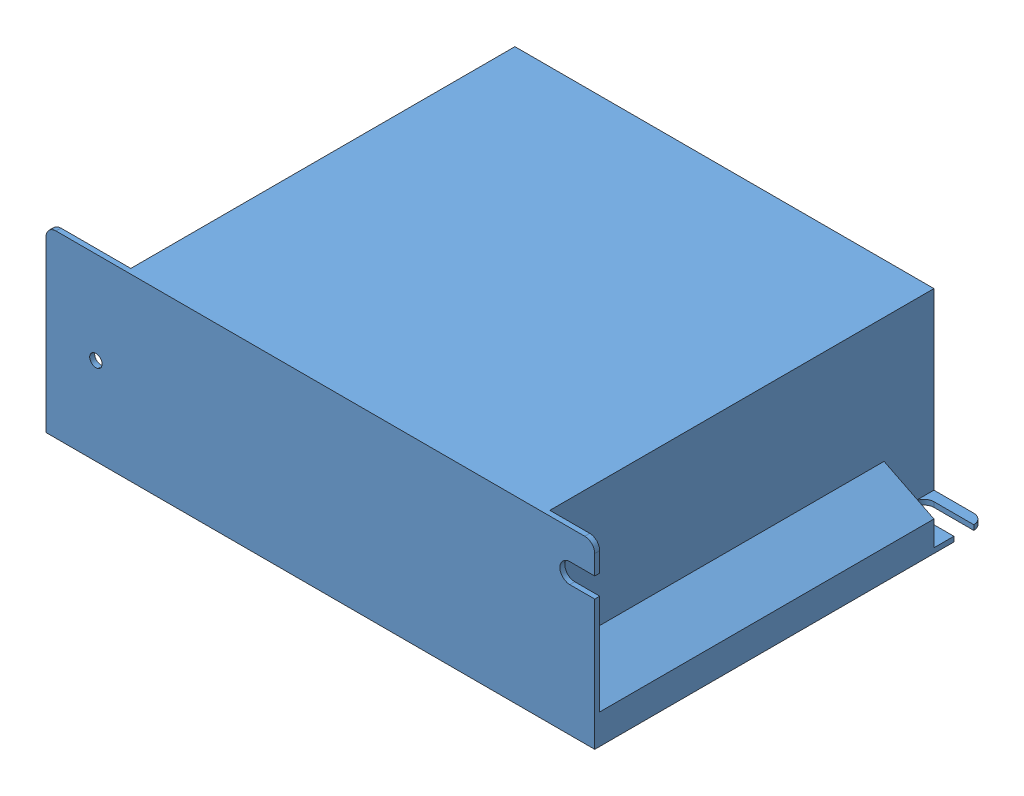
SolidWorks assembly PSU Assembly, configuration Default. Lengths in mm.
Overall size (110 36 78).
8 component instances, 4 part files, 16 mates.
Components (placement in the parent):
- case-1: case [Default] at origin size (110 36 78)
- conntectorblock-1: conntectorblock [Default] at (16 1 -68) x (-1 0 0) z (0 0 -1) size (15 16 50)
- pan head cross recess screw_iso-1: pan head cross recess screw_iso [ISO 7045 - M4 x 5 - Z - 5N] at (7 14.1 -23.3) x (0 -1 0) z (0.546944 0 -0.837169) size (8.02 8 8)
- pan head cross recess screw_iso-2: pan head cross recess screw_iso [ISO 7045 - M4 x 5 - Z - 5N] at (7 14.1 -33.1) x (0 -1 0) z (0 0 1) size (8.02 8 8)
- pan head cross recess screw_iso-3: pan head cross recess screw_iso [ISO 7045 - M4 x 5 - Z - 5N] at (7 14.1 -42.9) x (0 -1 0) z (0 0 1) size (8.02 8 8)
- pan head cross recess screw_iso-4: pan head cross recess screw_iso [ISO 7045 - M4 x 5 - Z - 5N] at (7 14.1 -52.7) x (0 -1 0) z (-0.546944 0 0.837169) size (8.02 8 8)
- pan head cross recess screw_iso-5: pan head cross recess screw_iso [ISO 7045 - M4 x 5 - Z - 5N] at (7 14.1 -62.5) x (0 -1 0) z (0 0 1) size (8.02 8 8)
- Screen connectorblock-1: Screen connectorblock [Default] at (16 17 -18) x (0 0 -1) z (1 0 0) size (50 3 15)
Mates (geometry in assembly coordinates):
- Coincident1: coincident: plane of case-1 through (16 1 -78) normal (-1 0 0); plane of conntectorblock-1 through (16 17 -68) normal (1 0 0)
- Coincident2: coincident: plane of case-1 through (0 1 0) normal (0 1 0); plane of conntectorblock-1 through (16 1 -68) normal (0 -1 0)
- Distance2: distance = 17 mm: plane of conntectorblock-1 through (16 17 -18) normal (0 0 1); plane of case-1 through (0 1 -1) normal (0 0 -1)
- Concentric1: concentric: cylinder of conntectorblock-1 through (7 11 -23.3) axis (0 1 0) radius 1.65; cylinder of pan head cross recess screw_iso-1 through (7 39.5 -23.3) axis (0 1 0) radius 4
- Coincident5: coincident: plane of conntectorblock-1 through (16 11 -68) normal (0 1 0); plane of pan head cross recess screw_iso-1 through (5.3257 11 -24.3939) normal (0 -1 0)
- Concentric2: concentric: cylinder of conntectorblock-1 through (7 11 -33.1) axis (0 1 0) radius 1.65; cylinder of pan head cross recess screw_iso-2 through (7 39.5 -33.1) axis (0 1 0) radius 4
- Coincident6: coincident: plane of conntectorblock-1 through (16 11 -68) normal (0 1 0); plane of pan head cross recess screw_iso-2 through (9 11 -33.1) normal (0 -1 0)
- Concentric3: concentric: cylinder of conntectorblock-1 through (7 11 -42.9) axis (0 1 0) radius 1.65; cylinder of pan head cross recess screw_iso-3 through (7 39.5 -42.9) axis (0 1 0) radius 4
- Coincident7: coincident: plane of conntectorblock-1 through (16 11 -68) normal (0 1 0); plane of pan head cross recess screw_iso-3 through (9 11 -42.9) normal (0 -1 0)
- Concentric4: concentric: cylinder of conntectorblock-1 through (7 11 -52.7) axis (0 1 0) radius 1.65; cylinder of pan head cross recess screw_iso-4 through (7 39.5 -52.7) axis (0 1 0) radius 4
- Coincident8: coincident: plane of conntectorblock-1 through (16 11 -68) normal (0 1 0); plane of pan head cross recess screw_iso-4 through (8.6743 11 -51.6061) normal (0 -1 0)
- Concentric5: concentric: cylinder of conntectorblock-1 through (7 11 -62.5) axis (0 1 0) radius 1.65; cylinder of pan head cross recess screw_iso-5 through (7 39.5 -62.5) axis (0 1 0) radius 4
- Coincident9: coincident: plane of conntectorblock-1 through (16 11 -68) normal (0 1 0); plane of pan head cross recess screw_iso-5 through (9 11 -62.5) normal (0 -1 0)
- Coincident10: coincident: plane of conntectorblock-1 through (16 17 -68) normal (0 1 0); plane of Screen connectorblock-1 through (16 17 -18) normal (0 -1 0)
- Coincident12: coincident: plane of conntectorblock-1 through (16 17 -68) normal (0 0 -1); plane of Screen connectorblock-1 through (16 20 -68) normal (0 0 -1)
- Coincident13: coincident: plane of conntectorblock-1 through (1 17 -68) normal (-1 0 0); plane of Screen connectorblock-1 through (1 20 -18) normal (-1 0 0)
